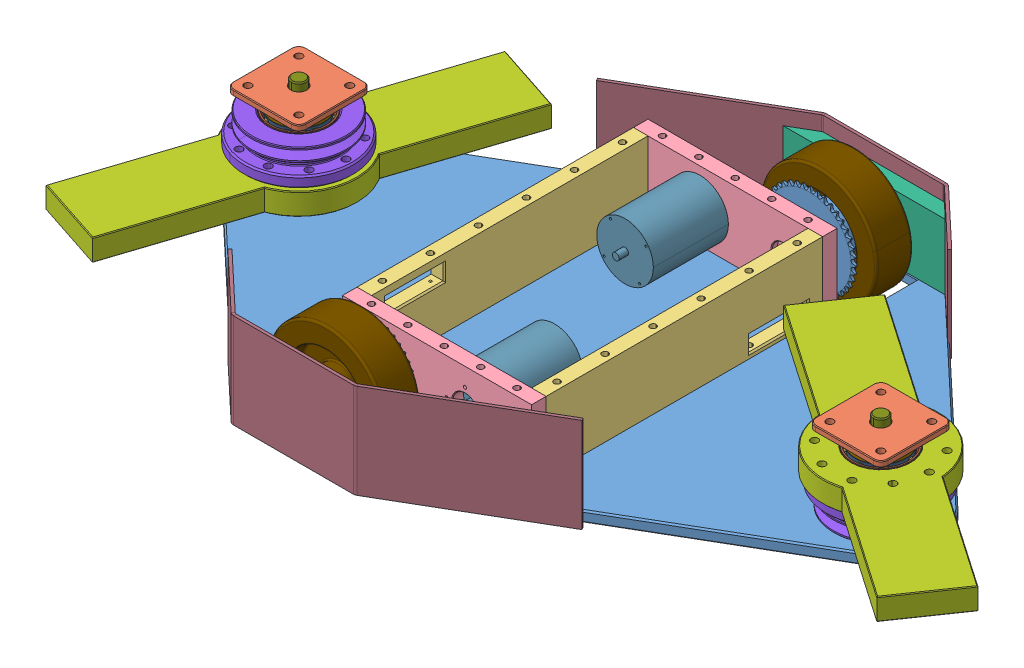
SolidWorks assembly ga2.1, configuration Default. Lengths in mm.
Overall size (1205.3 192.61 648).
86 component instances, 21 part files, 0 mates.
Components (placement in the parent):
- Copy of ga2.asm^ga2.1-1: Copy of ga2.asm^ga2.1 [Default] at origin size (1205.3 192.61 648) (virtual)
  - Copy of p101_baseplate_non_sheet.prt^Copy of ga2.asm_ga2.1-1: Copy of p101_baseplate_non_sheet.prt^Copy of ga2.asm_ga2.1 [Default] at origin size (950 15 640) (virtual)
  - Copy of p206_weapon_washer.prt^Copy of ga2.asm_ga2.1-1: Copy of p206_weapon_washer.prt^Copy of ga2.asm_ga2.1 [Default] at (350 0 50) size (100 8 100) (virtual)
  - Copy of p206_weapon_washer.prt^Copy of ga2.asm_ga2.1-2: Copy of p206_weapon_washer.prt^Copy of ga2.asm_ga2.1 [Default] at (-450 0 50) size (100 8 100) (virtual)
  - Copy of p401_verticalweb.prt^Copy of ga2.asm_ga2.1-1: Copy of p401_verticalweb.prt^Copy of ga2.asm_ga2.1 [Default] at (130 60 0) x (0 0 -1) z (-1 0 0) size (380.01 100.01 20) (virtual)
  - Copy of p401_verticalweb.prt^Copy of ga2.asm_ga2.1-2: Copy of p401_verticalweb.prt^Copy of ga2.asm_ga2.1 [Default] at (-110 60 0) x (0 0 1) z (-1 0 0) size (380.01 100.01 20) (virtual)
  - Copy of p402_verticalweb2.prt^Copy of ga2.asm_ga2.1-1: Copy of p402_verticalweb2.prt^Copy of ga2.asm_ga2.1 [Default] at (0 60 190) x (0 0 1) z (-1 0 0) size (20 100.01 260) (virtual)
  - Copy of p402_verticalweb2.prt^Copy of ga2.asm_ga2.1-2: Copy of p402_verticalweb2.prt^Copy of ga2.asm_ga2.1 [Default] at (0 60 -190) x (0 0 -1) z (1 0 0) size (20 100.01 260) (virtual)
  - Copy of p203_1_weapon_shaft.prt^Copy of ga2.asm_ga2.1-1: Copy of p203_1_weapon_shaft.prt^Copy of ga2.asm_ga2.1 [Default] at (-400 5 0) size (50 110 50) (virtual)
  - Copy of p203_1_weapon_shaft.prt^Copy of ga2.asm_ga2.1-2: Copy of p203_1_weapon_shaft.prt^Copy of ga2.asm_ga2.1 [Default] at (400 5 0) size (50 110 50) (virtual)
  - Copy of sideplate.prt^Copy of ga2.asm_ga2.1-1: Copy of sideplate.prt^Copy of ga2.asm_ga2.1 [Default] at (-85 15 320) x (-1 0 0) z (0 0 -1) size (225.51 90 20) (virtual)
  - Copy of sideplate.prt^Copy of ga2.asm_ga2.1-2: Copy of sideplate.prt^Copy of ga2.asm_ga2.1 [Default] at (85 15 -320) x (1 0 0) z (0 0 1) size (225.51 90 20) (virtual)
  - Copy of a200-2_blade.asm^Copy of ga2.asm_ga2.1-1: Copy of a200-2_blade.asm^Copy of ga2.asm_ga2.1 [Default] at (-430.541 20 253.1151) x (0.312169 0 -0.950027) z (0.950027 0 0.312169) size (500 81.5 160) (virtual)
    - Copy of p201-2_blade.prt^Copy of a200-2_blade.asm_Copy of ga2.asm_ga2.1-1: Copy of p201-2_blade.prt^Copy of a200-2_blade.asm_Copy of ga2.asm_ga2.1 [Default] at origin size (500 30.01 160) (virtual)
    - Copy of p202_2_blade_hub.prt^Copy of a200-2_blade.asm_Copy of ga2.asm_ga2.1-1: Copy of p202_2_blade_hub.prt^Copy of a200-2_blade.asm_Copy of ga2.asm_ga2.1 [Default] at (250 30 -50) size (150 57 150) (virtual)
    - Copy of wz107008050.asm^Copy of a200-2_blade.asm_Copy of ga2.asm_ga2.1-1: Copy of wz107008050.asm^Copy of a200-2_blade.asm_Copy of ga2.asm_ga2.1 [Default] at (250 56.5 -50) x (0 1 0) z (0 0 1) size (20.5 80 80) (virtual)
      - Copy of wz107008050_part1.prt^Copy of wz107008050.asm_Copy of a200-2_blade.asm_Copy of ga2.asm_ga2.1-1: Copy of wz107008050_part1.prt^Copy of wz107008050.asm_Copy of a200-2_blade.asm_Copy of ga2.asm_ga2.1 [Default] at origin size (20 67.5 67.5) (virtual)
      - Copy of wz107008050_part2.prt^Copy of wz107008050.asm_Copy of a200-2_blade.asm_Copy of ga2.asm_ga2.1-1: Copy of wz107008050_part2.prt^Copy of wz107008050.asm_Copy of a200-2_blade.asm_Copy of ga2.asm_ga2.1 [Default] at origin size (18.25 71.18 71.18) (virtual)
      - Copy of wz107008050_part3.prt^Copy of wz107008050.asm_Copy of a200-2_blade.asm_Copy of ga2.asm_ga2.1-1: Copy of wz107008050_part3.prt^Copy of wz107008050.asm_Copy of a200-2_blade.asm_Copy of ga2.asm_ga2.1 [Default] at origin size (15.5 80 80) (virtual)
      - Copy of wz107008050_part4.prt^Copy of wz107008050.asm_Copy of a200-2_blade.asm_Copy of ga2.asm_ga2.1-1: Copy of wz107008050_part4.prt^Copy of wz107008050.asm_Copy of a200-2_blade.asm_Copy of ga2.asm_ga2.1 [Default] at origin size (13.5 7.77 5.21) (virtual)
      - Copy of wz107008050_part4.prt^Copy of wz107008050.asm_Copy of a200-2_blade.asm_Copy of ga2.asm_ga2.1-2: Copy of wz107008050_part4.prt^Copy of wz107008050.asm_Copy of a200-2_blade.asm_Copy of ga2.asm_ga2.1 [Default] x (1 0 0) z (0 0.707107 0.707107) size (13.5 7.77 5.21) (virtual)
      - Copy of wz107008050_part4.prt^Copy of wz107008050.asm_Copy of a200-2_blade.asm_Copy of ga2.asm_ga2.1-3: Copy of wz107008050_part4.prt^Copy of wz107008050.asm_Copy of a200-2_blade.asm_Copy of ga2.asm_ga2.1 [Default] x (1 0 0) z (0 1 0) size (13.5 7.77 5.21) (virtual)
      - Copy of wz107008050_part4.prt^Copy of wz107008050.asm_Copy of a200-2_blade.asm_Copy of ga2.asm_ga2.1-4: Copy of wz107008050_part4.prt^Copy of wz107008050.asm_Copy of a200-2_blade.asm_Copy of ga2.asm_ga2.1 [Default] x (1 0 0) z (0 0.707107 -0.707107) size (13.5 7.77 5.21) (virtual)
      - Copy of wz107008050_part4.prt^Copy of wz107008050.asm_Copy of a200-2_blade.asm_Copy of ga2.asm_ga2.1-5: Copy of wz107008050_part4.prt^Copy of wz107008050.asm_Copy of a200-2_blade.asm_Copy of ga2.asm_ga2.1 [Default] x (1 0 0) z (0 0 -1) size (13.5 7.77 5.21) (virtual)
      - Copy of wz107008050_part4.prt^Copy of wz107008050.asm_Copy of a200-2_blade.asm_Copy of ga2.asm_ga2.1-6: Copy of wz107008050_part4.prt^Copy of wz107008050.asm_Copy of a200-2_blade.asm_Copy of ga2.asm_ga2.1 [Default] x (1 0 0) z (0 -0.707107 -0.707107) size (13.5 7.77 5.21) (virtual)
      - Copy of wz107008050_part4.prt^Copy of wz107008050.asm_Copy of a200-2_blade.asm_Copy of ga2.asm_ga2.1-7: Copy of wz107008050_part4.prt^Copy of wz107008050.asm_Copy of a200-2_blade.asm_Copy of ga2.asm_ga2.1 [Default] x (1 0 0) z (0 -1 0) size (13.5 7.77 5.21) (virtual)
      - Copy of wz107008050_part4.prt^Copy of wz107008050.asm_Copy of a200-2_blade.asm_Copy of ga2.asm_ga2.1-8: Copy of wz107008050_part4.prt^Copy of wz107008050.asm_Copy of a200-2_blade.asm_Copy of ga2.asm_ga2.1 [Default] x (1 0 0) z (0 -0.707107 0.707107) size (13.5 7.77 5.21) (virtual)
    - Copy of wz107008050.asm^Copy of a200-2_blade.asm_Copy of ga2.asm_ga2.1-2: Copy of wz107008050.asm^Copy of a200-2_blade.asm_Copy of ga2.asm_ga2.1 [Default] at (250 15 -50) x (0 -1 0) z (0 0 1) size (20.5 80 80) (virtual)
      - Copy of wz107008050_part1.prt^Copy of wz107008050.asm_Copy of a200-2_blade.asm_Copy of ga2.asm_ga2.1-1: Copy of wz107008050_part1.prt^Copy of wz107008050.asm_Copy of a200-2_blade.asm_Copy of ga2.asm_ga2.1 [Default] at origin size (20 67.5 67.5) (virtual)
      - Copy of wz107008050_part2.prt^Copy of wz107008050.asm_Copy of a200-2_blade.asm_Copy of ga2.asm_ga2.1-1: Copy of wz107008050_part2.prt^Copy of wz107008050.asm_Copy of a200-2_blade.asm_Copy of ga2.asm_ga2.1 [Default] at origin size (18.25 71.18 71.18) (virtual)
      - Copy of wz107008050_part3.prt^Copy of wz107008050.asm_Copy of a200-2_blade.asm_Copy of ga2.asm_ga2.1-1: Copy of wz107008050_part3.prt^Copy of wz107008050.asm_Copy of a200-2_blade.asm_Copy of ga2.asm_ga2.1 [Default] at origin size (15.5 80 80) (virtual)
      - Copy of wz107008050_part4.prt^Copy of wz107008050.asm_Copy of a200-2_blade.asm_Copy of ga2.asm_ga2.1-1: Copy of wz107008050_part4.prt^Copy of wz107008050.asm_Copy of a200-2_blade.asm_Copy of ga2.asm_ga2.1 [Default] at origin size (13.5 7.77 5.21) (virtual)
      - Copy of wz107008050_part4.prt^Copy of wz107008050.asm_Copy of a200-2_blade.asm_Copy of ga2.asm_ga2.1-2: Copy of wz107008050_part4.prt^Copy of wz107008050.asm_Copy of a200-2_blade.asm_Copy of ga2.asm_ga2.1 [Default] x (1 0 0) z (0 0.707107 0.707107) size (13.5 7.77 5.21) (virtual)
      - Copy of wz107008050_part4.prt^Copy of wz107008050.asm_Copy of a200-2_blade.asm_Copy of ga2.asm_ga2.1-3: Copy of wz107008050_part4.prt^Copy of wz107008050.asm_Copy of a200-2_blade.asm_Copy of ga2.asm_ga2.1 [Default] x (1 0 0) z (0 1 0) size (13.5 7.77 5.21) (virtual)
      - Copy of wz107008050_part4.prt^Copy of wz107008050.asm_Copy of a200-2_blade.asm_Copy of ga2.asm_ga2.1-4: Copy of wz107008050_part4.prt^Copy of wz107008050.asm_Copy of a200-2_blade.asm_Copy of ga2.asm_ga2.1 [Default] x (1 0 0) z (0 0.707107 -0.707107) size (13.5 7.77 5.21) (virtual)
      - Copy of wz107008050_part4.prt^Copy of wz107008050.asm_Copy of a200-2_blade.asm_Copy of ga2.asm_ga2.1-5: Copy of wz107008050_part4.prt^Copy of wz107008050.asm_Copy of a200-2_blade.asm_Copy of ga2.asm_ga2.1 [Default] x (1 0 0) z (0 0 -1) size (13.5 7.77 5.21) (virtual)
      - Copy of wz107008050_part4.prt^Copy of wz107008050.asm_Copy of a200-2_blade.asm_Copy of ga2.asm_ga2.1-6: Copy of wz107008050_part4.prt^Copy of wz107008050.asm_Copy of a200-2_blade.asm_Copy of ga2.asm_ga2.1 [Default] x (1 0 0) z (0 -0.707107 -0.707107) size (13.5 7.77 5.21) (virtual)
      - Copy of wz107008050_part4.prt^Copy of wz107008050.asm_Copy of a200-2_blade.asm_Copy of ga2.asm_ga2.1-7: Copy of wz107008050_part4.prt^Copy of wz107008050.asm_Copy of a200-2_blade.asm_Copy of ga2.asm_ga2.1 [Default] x (1 0 0) z (0 -1 0) size (13.5 7.77 5.21) (virtual)
      - Copy of wz107008050_part4.prt^Copy of wz107008050.asm_Copy of a200-2_blade.asm_Copy of ga2.asm_ga2.1-8: Copy of wz107008050_part4.prt^Copy of wz107008050.asm_Copy of a200-2_blade.asm_Copy of ga2.asm_ga2.1 [Default] x (1 0 0) z (0 -0.707107 0.707107) size (13.5 7.77 5.21) (virtual)
  - Copy of a200-2_blade.asm^Copy of ga2.asm_ga2.1-2: Copy of a200-2_blade.asm^Copy of ga2.asm_ga2.1 [Default] at (222.4993 91.5 -183.0123) x (0.823474 0 0.567354) z (0.567354 0 -0.823474) size (500 81.5 160) (virtual)
    - Copy of p201-2_blade.prt^Copy of a200-2_blade.asm_Copy of ga2.asm_ga2.1-1: Copy of p201-2_blade.prt^Copy of a200-2_blade.asm_Copy of ga2.asm_ga2.1 [Default] at origin size (500 30.01 160) (virtual)
    - Copy of p202_2_blade_hub.prt^Copy of a200-2_blade.asm_Copy of ga2.asm_ga2.1-1: Copy of p202_2_blade_hub.prt^Copy of a200-2_blade.asm_Copy of ga2.asm_ga2.1 [Default] at (250 30 -50) size (150 57 150) (virtual)
    - Copy of wz107008050.asm^Copy of a200-2_blade.asm_Copy of ga2.asm_ga2.1-1: Copy of wz107008050.asm^Copy of a200-2_blade.asm_Copy of ga2.asm_ga2.1 [Default] at (250 56.5 -50) x (0 1 0) z (0 0 1) size (20.5 80 80) (virtual)
      - Copy of wz107008050_part1.prt^Copy of wz107008050.asm_Copy of a200-2_blade.asm_Copy of ga2.asm_ga2.1-1: Copy of wz107008050_part1.prt^Copy of wz107008050.asm_Copy of a200-2_blade.asm_Copy of ga2.asm_ga2.1 [Default] at origin size (20 67.5 67.5) (virtual)
      - Copy of wz107008050_part2.prt^Copy of wz107008050.asm_Copy of a200-2_blade.asm_Copy of ga2.asm_ga2.1-1: Copy of wz107008050_part2.prt^Copy of wz107008050.asm_Copy of a200-2_blade.asm_Copy of ga2.asm_ga2.1 [Default] at origin size (18.25 71.18 71.18) (virtual)
      - Copy of wz107008050_part3.prt^Copy of wz107008050.asm_Copy of a200-2_blade.asm_Copy of ga2.asm_ga2.1-1: Copy of wz107008050_part3.prt^Copy of wz107008050.asm_Copy of a200-2_blade.asm_Copy of ga2.asm_ga2.1 [Default] at origin size (15.5 80 80) (virtual)
      - Copy of wz107008050_part4.prt^Copy of wz107008050.asm_Copy of a200-2_blade.asm_Copy of ga2.asm_ga2.1-1: Copy of wz107008050_part4.prt^Copy of wz107008050.asm_Copy of a200-2_blade.asm_Copy of ga2.asm_ga2.1 [Default] at origin size (13.5 7.77 5.21) (virtual)
      - Copy of wz107008050_part4.prt^Copy of wz107008050.asm_Copy of a200-2_blade.asm_Copy of ga2.asm_ga2.1-2: Copy of wz107008050_part4.prt^Copy of wz107008050.asm_Copy of a200-2_blade.asm_Copy of ga2.asm_ga2.1 [Default] x (1 0 0) z (0 0.707107 0.707107) size (13.5 7.77 5.21) (virtual)
      - Copy of wz107008050_part4.prt^Copy of wz107008050.asm_Copy of a200-2_blade.asm_Copy of ga2.asm_ga2.1-3: Copy of wz107008050_part4.prt^Copy of wz107008050.asm_Copy of a200-2_blade.asm_Copy of ga2.asm_ga2.1 [Default] x (1 0 0) z (0 1 0) size (13.5 7.77 5.21) (virtual)
      - Copy of wz107008050_part4.prt^Copy of wz107008050.asm_Copy of a200-2_blade.asm_Copy of ga2.asm_ga2.1-4: Copy of wz107008050_part4.prt^Copy of wz107008050.asm_Copy of a200-2_blade.asm_Copy of ga2.asm_ga2.1 [Default] x (1 0 0) z (0 0.707107 -0.707107) size (13.5 7.77 5.21) (virtual)
      - Copy of wz107008050_part4.prt^Copy of wz107008050.asm_Copy of a200-2_blade.asm_Copy of ga2.asm_ga2.1-5: Copy of wz107008050_part4.prt^Copy of wz107008050.asm_Copy of a200-2_blade.asm_Copy of ga2.asm_ga2.1 [Default] x (1 0 0) z (0 0 -1) size (13.5 7.77 5.21) (virtual)
      - Copy of wz107008050_part4.prt^Copy of wz107008050.asm_Copy of a200-2_blade.asm_Copy of ga2.asm_ga2.1-6: Copy of wz107008050_part4.prt^Copy of wz107008050.asm_Copy of a200-2_blade.asm_Copy of ga2.asm_ga2.1 [Default] x (1 0 0) z (0 -0.707107 -0.707107) size (13.5 7.77 5.21) (virtual)
      - Copy of wz107008050_part4.prt^Copy of wz107008050.asm_Copy of a200-2_blade.asm_Copy of ga2.asm_ga2.1-7: Copy of wz107008050_part4.prt^Copy of wz107008050.asm_Copy of a200-2_blade.asm_Copy of ga2.asm_ga2.1 [Default] x (1 0 0) z (0 -1 0) size (13.5 7.77 5.21) (virtual)
      - Copy of wz107008050_part4.prt^Copy of wz107008050.asm_Copy of a200-2_blade.asm_Copy of ga2.asm_ga2.1-8: Copy of wz107008050_part4.prt^Copy of wz107008050.asm_Copy of a200-2_blade.asm_Copy of ga2.asm_ga2.1 [Default] x (1 0 0) z (0 -0.707107 0.707107) size (13.5 7.77 5.21) (virtual)
    - Copy of wz107008050.asm^Copy of a200-2_blade.asm_Copy of ga2.asm_ga2.1-2: Copy of wz107008050.asm^Copy of a200-2_blade.asm_Copy of ga2.asm_ga2.1 [Default] at (250 15 -50) x (0 -1 0) z (0 0 1) size (20.5 80 80) (virtual)
      - Copy of wz107008050_part1.prt^Copy of wz107008050.asm_Copy of a200-2_blade.asm_Copy of ga2.asm_ga2.1-1: Copy of wz107008050_part1.prt^Copy of wz107008050.asm_Copy of a200-2_blade.asm_Copy of ga2.asm_ga2.1 [Default] at origin size (20 67.5 67.5) (virtual)
      - Copy of wz107008050_part2.prt^Copy of wz107008050.asm_Copy of a200-2_blade.asm_Copy of ga2.asm_ga2.1-1: Copy of wz107008050_part2.prt^Copy of wz107008050.asm_Copy of a200-2_blade.asm_Copy of ga2.asm_ga2.1 [Default] at origin size (18.25 71.18 71.18) (virtual)
      - Copy of wz107008050_part3.prt^Copy of wz107008050.asm_Copy of a200-2_blade.asm_Copy of ga2.asm_ga2.1-1: Copy of wz107008050_part3.prt^Copy of wz107008050.asm_Copy of a200-2_blade.asm_Copy of ga2.asm_ga2.1 [Default] at origin size (15.5 80 80) (virtual)
      - Copy of wz107008050_part4.prt^Copy of wz107008050.asm_Copy of a200-2_blade.asm_Copy of ga2.asm_ga2.1-1: Copy of wz107008050_part4.prt^Copy of wz107008050.asm_Copy of a200-2_blade.asm_Copy of ga2.asm_ga2.1 [Default] at origin size (13.5 7.77 5.21) (virtual)
      - Copy of wz107008050_part4.prt^Copy of wz107008050.asm_Copy of a200-2_blade.asm_Copy of ga2.asm_ga2.1-2: Copy of wz107008050_part4.prt^Copy of wz107008050.asm_Copy of a200-2_blade.asm_Copy of ga2.asm_ga2.1 [Default] x (1 0 0) z (0 0.707107 0.707107) size (13.5 7.77 5.21) (virtual)
      - Copy of wz107008050_part4.prt^Copy of wz107008050.asm_Copy of a200-2_blade.asm_Copy of ga2.asm_ga2.1-3: Copy of wz107008050_part4.prt^Copy of wz107008050.asm_Copy of a200-2_blade.asm_Copy of ga2.asm_ga2.1 [Default] x (1 0 0) z (0 1 0) size (13.5 7.77 5.21) (virtual)
      - Copy of wz107008050_part4.prt^Copy of wz107008050.asm_Copy of a200-2_blade.asm_Copy of ga2.asm_ga2.1-4: Copy of wz107008050_part4.prt^Copy of wz107008050.asm_Copy of a200-2_blade.asm_Copy of ga2.asm_ga2.1 [Default] x (1 0 0) z (0 0.707107 -0.707107) size (13.5 7.77 5.21) (virtual)
      - Copy of wz107008050_part4.prt^Copy of wz107008050.asm_Copy of a200-2_blade.asm_Copy of ga2.asm_ga2.1-5: Copy of wz107008050_part4.prt^Copy of wz107008050.asm_Copy of a200-2_blade.asm_Copy of ga2.asm_ga2.1 [Default] x (1 0 0) z (0 0 -1) size (13.5 7.77 5.21) (virtual)
      - Copy of wz107008050_part4.prt^Copy of wz107008050.asm_Copy of a200-2_blade.asm_Copy of ga2.asm_ga2.1-6: Copy of wz107008050_part4.prt^Copy of wz107008050.asm_Copy of a200-2_blade.asm_Copy of ga2.asm_ga2.1 [Default] x (1 0 0) z (0 -0.707107 -0.707107) size (13.5 7.77 5.21) (virtual)
      - Copy of wz107008050_part4.prt^Copy of wz107008050.asm_Copy of a200-2_blade.asm_Copy of ga2.asm_ga2.1-7: Copy of wz107008050_part4.prt^Copy of wz107008050.asm_Copy of a200-2_blade.asm_Copy of ga2.asm_ga2.1 [Default] x (1 0 0) z (0 -1 0) size (13.5 7.77 5.21) (virtual)
      - Copy of wz107008050_part4.prt^Copy of wz107008050.asm_Copy of a200-2_blade.asm_Copy of ga2.asm_ga2.1-8: Copy of wz107008050_part4.prt^Copy of wz107008050.asm_Copy of a200-2_blade.asm_Copy of ga2.asm_ga2.1 [Default] x (1 0 0) z (0 -0.707107 0.707107) size (13.5 7.77 5.21) (virtual)
  - Copy of p102-3_top_plate.prt^Copy of ga2.asm_ga2.1-1: Copy of p102-3_top_plate.prt^Copy of ga2.asm_ga2.1 [Default] at (0 120 0) x (1 0 0) z (0 0 -1) size (950 15 640) (hidden, virtual)
  - Copy of p501_hardox_right.prt^Copy of ga2.asm_ga2.1-1: Copy of p501_hardox_right.prt^Copy of ga2.asm_ga2.1 [Default] at (-168.9192 -5 324) x (1 0 0) z (0 0 1) size (447.32 130 118.46) (virtual)
  - Copy of p501_hardox_right.prt^Copy of ga2.asm_ga2.1-2: Copy of p501_hardox_right.prt^Copy of ga2.asm_ga2.1 [Default] at (168.9192 -5 -324) x (-1 0 0) z (0 0 -1) size (447.32 130 118.46) (virtual)
  - Copy of p103_top_hatch.prt^Copy of ga2.asm_ga2.1-1: Copy of p103_top_hatch.prt^Copy of ga2.asm_ga2.1 [Default] at (-100 122.5 -180) x (1 0 0) z (0 0 -1) size (200 25 360) (hidden, virtual)
  - Copy of ampflow_e30_150.prt^Copy of ga2.asm_ga2.1-1: Copy of ampflow_e30_150.prt^Copy of ga2.asm_ga2.1 [Default] at (38.45 60 190) size (77.73 77.73 166.63) (virtual)
  - Copy of ampflow_e30_150.prt^Copy of ga2.asm_ga2.1-2: Copy of ampflow_e30_150.prt^Copy of ga2.asm_ga2.1 [Default] at (-38.45 60 -190) x (1 0 0) z (0 0 -1) size (77.73 77.73 166.63) (virtual)
  - Copy of bandbmnfg_35b8.prt^Copy of ga2.asm_ga2.1-1: Copy of bandbmnfg_35b8.prt^Copy of ga2.asm_ga2.1 [Default] at (38.45 60 229.05) x (0 0 -1) z (0.416176 -0.909284 0) size (19.05 27.51 27.51) (virtual)
  - Copy of bandbmnfg_35b8.prt^Copy of ga2.asm_ga2.1-2: Copy of bandbmnfg_35b8.prt^Copy of ga2.asm_ga2.1 [Default] at (-38.45 60 -229.05) x (0 0 1) z (0.745955 -0.665996 0) size (19.05 27.51 27.51) (virtual)
  - Copy of p206_weapon_washer.prt^Copy of ga2.asm_ga2.1-3: Copy of p206_weapon_washer.prt^Copy of ga2.asm_ga2.1 [Default] at (350 120 -50) x (1 0 0) z (0 0 -1) size (100 8 100) (virtual)
  - Copy of p205_2_m20_hex_head.prt^Copy of ga2.asm_ga2.1-1: Copy of p205_2_m20_hex_head.prt^Copy of ga2.asm_ga2.1 [Default] at (400 0 0) x (0 1 0) z (0 0 1) size (140.01 34.66 30.02) (virtual)
  - Copy of p206_weapon_washer.prt^Copy of ga2.asm_ga2.1-4: Copy of p206_weapon_washer.prt^Copy of ga2.asm_ga2.1 [Default] at (-450 120 -50) x (1 0 0) z (0 0 -1) size (100 8 100) (virtual)
  - Copy of p205_2_m20_hex_head.prt^Copy of ga2.asm_ga2.1-2: Copy of p205_2_m20_hex_head.prt^Copy of ga2.asm_ga2.1 [Default] at (-400 0 0) x (0 1 0) z (0 0 1) size (140.01 34.66 30.02) (virtual)
  - Copy of p302-2_wheelshaft.prt^Copy of ga2.asm_ga2.1-1: Copy of p302-2_wheelshaft.prt^Copy of ga2.asm_ga2.1 [Default] at (-75 60 261.1237) x (1 0 0) z (0 1 0) size (25 129.05 25) (virtual)
  - Copy of p302-2_wheelshaft.prt^Copy of ga2.asm_ga2.1-2: Copy of p302-2_wheelshaft.prt^Copy of ga2.asm_ga2.1 [Default] at (75 60 -261.1237) x (-1 0 0) z (0 1 0) size (25 129.05 25) (virtual)
  - Copy of a300_wheel.asm^Copy of ga2.asm_ga2.1-1: Copy of a300_wheel.asm^Copy of ga2.asm_ga2.1 [Default] at (75 60 -264.0629) x (-0.972992 -0.230838 0) z (-0.230838 0.972992 0) size (160 68 160) (virtual)
    - Copy of p301_blue_wheel.prt^Copy of a300_wheel.asm_Copy of ga2.asm_ga2.1-1: Copy of p301_blue_wheel.prt^Copy of a300_wheel.asm_Copy of ga2.asm_ga2.1 [Default] at origin size (160 60 160) (virtual)
    - Copy of p303_sprocket_3-8_40t.prt^Copy of a300_wheel.asm_Copy of ga2.asm_ga2.1-1: Copy of p303_sprocket_3-8_40t.prt^Copy of a300_wheel.asm_Copy of ga2.asm_ga2.1 [Default] at (0 38 0) x (0 -1 0) z (0 0 1) size (30 126.47 126.47) (virtual)
  - Copy of a300_wheel.asm^Copy of ga2.asm_ga2.1-2: Copy of a300_wheel.asm^Copy of ga2.asm_ga2.1 [Default] at (-75 60 263) x (0.986196 0.165582 0) z (-0.165582 0.986196 0) size (160 68 160) (virtual)
    - Copy of p301_blue_wheel.prt^Copy of a300_wheel.asm_Copy of ga2.asm_ga2.1-1: Copy of p301_blue_wheel.prt^Copy of a300_wheel.asm_Copy of ga2.asm_ga2.1 [Default] at origin size (160 60 160) (virtual)
    - Copy of p303_sprocket_3-8_40t.prt^Copy of a300_wheel.asm_Copy of ga2.asm_ga2.1-1: Copy of p303_sprocket_3-8_40t.prt^Copy of a300_wheel.asm_Copy of ga2.asm_ga2.1 [Default] at (0 38 0) x (0 -1 0) z (0 0 1) size (30 126.47 126.47) (virtual)
